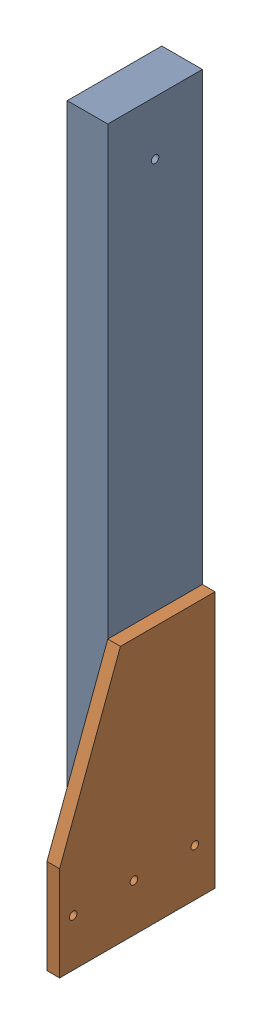
SolidWorks assembly TE-23032, configuration Default. Lengths in mm.
Overall size (50.01 660.4 146.05).
2 component instances, 2 part files, 3 mates.
Components (placement in the parent):
- TE-23011-1: TE-23011 [Default] at (-254 660.4 44.45) x (1 0 0) z (0 -1 0) size (38.1 88.9 571.5)
- TE-23012-1: TE-23012 [Default] at (-223.0438 0 0) x (-1 0 0) z (0 0 -1) size (11.91 241.3 146.05)
Mates (geometry in assembly coordinates):
- Coincident1: coincident: plane of Cone Ramp Vertical-1 through (-273.05 88.9 0) normal (0 0 -1); plane of Cone Ramp Gusset-1 through (-234.95 60.298 0) normal (0 0 -1)
- Coincident2: coincident: plane of Cone Ramp Vertical-1 through (-234.95 88.9 0) normal (1 0 0); plane of Cone Ramp Gusset-1 through (-234.95 60.298 0) normal (-1 0 0)
- Distance1: distance = 88.9 mm aligned: plane of Cone Ramp Gusset-1 through (-234.95 0 146.05) normal (0 -1 0); plane of Cone Ramp Vertical-1 through (-254 88.9 44.45) normal (0 -1 0)
